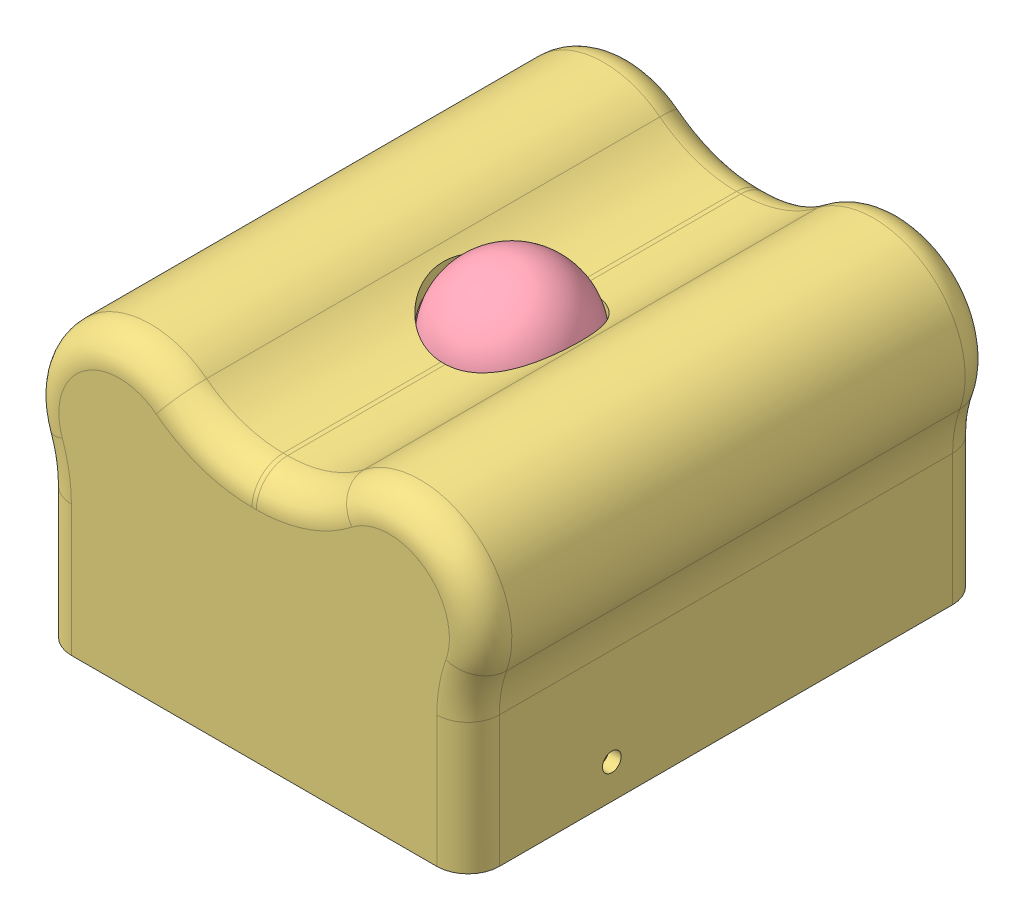
SolidWorks assembly ProtoHosing, configuration Default. Lengths in mm.
Overall size (72.5 49 82.55).
4 component instances, 4 part files, 12 mates.
Components (placement in the parent):
- PCB-1: PCB [Default] at (0 34.5 0) x (0 0 -1) z (-1 0 0) size (76.5 20.67 59.66)
- BackPlate2-1: BackPlate2 [Default] at origin size (64.5 8 78.55)
- Proto3Front-1: Proto3Front [Default] at (0 20 0) x (1 0 0) z (0 -1 0) size (72.5 82.55 47.27)
- PIR-1: PIR [Default] at (0 34.5 0) size (28.74 14.5 33.5)
Mates (geometry in assembly coordinates):
- Coincident1: coincident aligned: plane of BackPlate2-1 through (0 0 0) normal (0 1 0); plane of assembly through (0 0 0) normal (0 1 0)
- Coincident2: coincident aligned: plane of BackPlate2-1 through (0 0 0) normal (1 0 0); plane of assembly through (0 0 0) normal (1 0 0)
- Coincident3: coincident aligned: plane of BackPlate2-1 through (0 0 0) normal (0 0 1); plane of assembly through (0 0 0) normal (0 0 1)
- Coincident6: coincident aligned: plane of Proto3Front-1; plane of assembly through (0 0 0) normal (1 0 0)
- Coincident7: coincident aligned: plane of Proto3Front-1 through (0 20 0) normal (0 0 1); plane of assembly through (0 0 0) normal (0 0 1)
- Coincident8: coincident anti-aligned: plane of PCB-1 through (0 34.5 0) normal (-1 0 0); plane of assembly through (0 0 0) normal (1 0 0)
- Parallel1: parallel anti-aligned: plane of PCB-1; plane of assembly through (0 0 0) normal (0 1 0)
- Coincident9: coincident anti-aligned: plane of PCB-1; plane of assembly through (0 0 0) normal (0 0 1)
- Concentric1: concentric anti-aligned: cylinder of Proto3Front-1 through (0 47.2694 0) axis (0 -1 0) radius 11; circle of PIR-1
- Coincident10: coincident anti-aligned: plane of Proto3Front-1 through (0 38 41.275) normal (0 -1 0); plane of PIR-1 through (0 38 0) normal (0 1 0)
- Coincident11: coincident anti-aligned: plane of PCB-1 through (0 34.5 0) normal (0 1 0); plane of PIR-1 through (0 34.5 0) normal (0 -1 0)
- Coincident12: coincident aligned: plane of BackPlate2-1 through (29.25 0 36.275) normal (0 -1 0); plane of Proto3Front-1 through (0 0 41.275) normal (0 -1 0)
